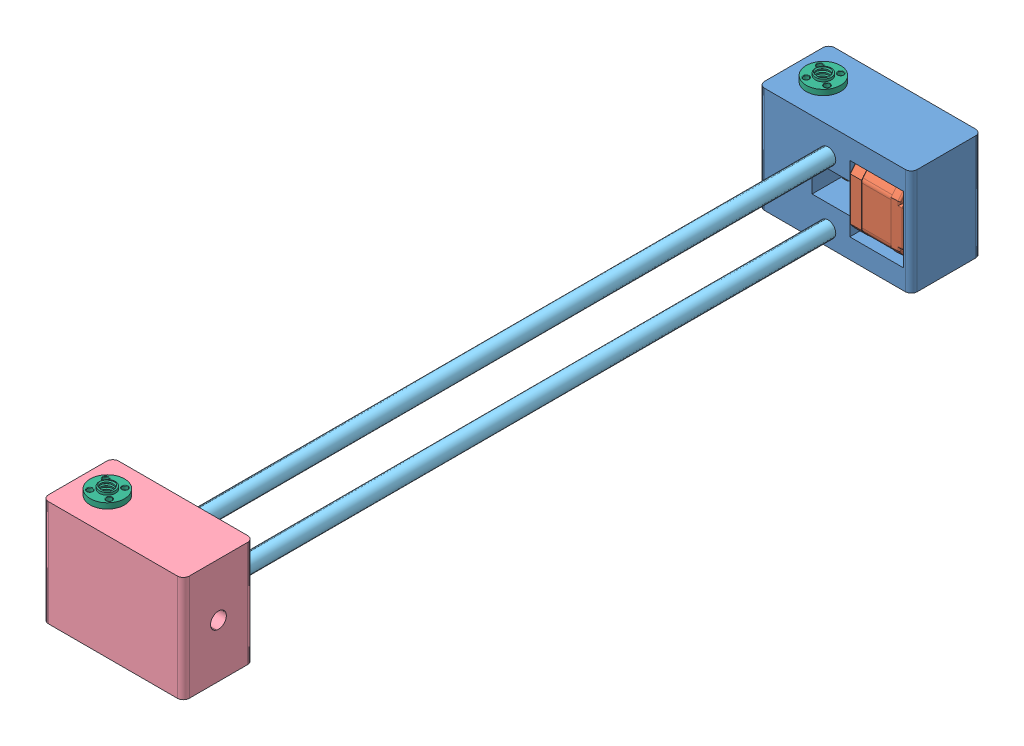
SolidWorks assembly Hot end shaft unit, configuration Default. Lengths in mm.
Overall size (97.79 73.34 503.43).
9 component instances, 6 part files, 27 mates.
Components (placement in the parent):
- Hot end motor housing-1: Hot end motor housing [Default] at (79.4555 45.3939 50.1961) size (97.79 67.82 44.96)
- Stepper Motor-1: Stepper Motor [6627T66] at (87.0755 66.6029 71.4051) x (0 0 1) z (-1 0 0) size (42.42 42.97 58.17)
- Timing Belt Sprocket-1: Timing Belt Sprocket [Défaut] at (82.5797 66.6029 71.4051) x (0 -0.226657 0.973975) z (-1 0 0) size (17.4 17.4 14.3)
- Hot end housing-1: Hot end housing [Default] at (28.6555 32.6939 551.0841) x (0 0 -1) z (1 0 0) size (44.96 67.82 90.17)
- Linear shaft 10mm-1: Linear shaft 10mm [6459K16] at (73.1055 83.3539 299.3701) size (10 10 426.21)
- Linear shaft 10mm-2: Linear shaft 10mm [6459K16] at (73.1055 42.8539 299.3701) size (10 10 426.21)
- Timing Belt Sprocket-2: Timing Belt Sprocket [Défaut] at (82.5035 66.7299 528.6051) x (0 0 1) z (-1 0 0) size (17.4 17.4 14.3)
- LeadScrew_Nut-1: LeadScrew_Nut [Default] at (47.7055 104.0119 70.1351) x (-0.837169 0 -0.546944) z (0 1 0) size (22 22 16.05)
- LeadScrew_Nut-2: LeadScrew_Nut [Default] at (47.7055 104.0119 528.6051) x (-0.773768 0 -0.633469) z (0 1 0) size (22 22 16.05)
Mates (geometry in assembly coordinates):
- Coincident1: coincident anti-aligned: plane of Hot end motor housing-1 through (79.4555 45.3939 50.1961) normal (0 0 1); plane of Stepper Motor-1 through (94.6447 52.7191 50.1961) normal (0 0 -1)
- Coincident2: coincident anti-aligned: plane of Hot end motor housing-1 through (121.3655 45.3939 92.6141) normal (-1 0 0); plane of Stepper Motor-1 through (121.3655 66.6029 71.4051) normal (1 0 0)
- Coincident3: coincident anti-aligned: plane of Hot end motor housing-1 through (87.0755 45.3939 92.6141) normal (0 1 0); plane of Stepper Motor-1 through (94.6447 45.3939 85.2889) normal (0 -1 0)
- Concentric2: concentric anti-aligned: cylinder of Stepper Motor-1 through (63.1995 66.6029 71.4051) axis (-1 0 0) radius 2.4956; cylinder of Timing Belt Sprocket-1 through (68.2795 66.6029 71.4051) axis (1 0 0) radius 3.175
- Distance1: distance = 5.08 mm aligned: plane of Stepper Motor-1 through (63.1995 69.0985 71.4051) normal (-1 0 0); plane of Timing Belt Sprocket-1 through (68.2795 66.6029 71.4051) normal (-1 0 0)
- Parallel1: parallel aligned: plane of Hot end motor housing-1 through (79.4555 45.3939 92.6141) normal (0 0 1); plane of Hot end housing-1 through (118.8255 32.6939 551.0841) normal (0 0 1)
- Coincident7: coincident aligned: plane of Hot end motor housing-1 through (28.6555 100.5119 92.6141) normal (0 1 0); plane of Hot end housing-1 through (118.8255 100.5119 551.0841) normal (0 1 0)
- Distance2: distance = 458.47 mm: cylinder of Hot end housing-1 through (47.7055 85.2719 528.6051) axis (0 1 0) radius 5.1; cylinder of Hot end motor housing-1 through (47.7055 85.2719 70.1351) axis (0 1 0) radius 5.1
- Concentric4: concentric anti-aligned: cylinder of Hot end motor housing-1 through (73.1055 83.3539 86.2641) axis (0 0 1) radius 5; cylinder of Linear shaft 10mm-1 through (73.1055 83.3539 512.4761) axis (0 0 -1) radius 5
- Coincident10: coincident anti-aligned: plane of Hot end housing-1 through (73.1055 83.3539 512.4761) normal (0 0 -1); plane of Linear shaft 10mm-1 through (73.1055 83.3539 512.4761) normal (0 0 1)
- Concentric5: concentric aligned: cylinder of Hot end housing-1 through (73.1055 42.8539 512.4761) axis (0 0 -1) radius 5; cylinder of Linear shaft 10mm-2 through (73.1055 42.8539 512.4761) axis (0 0 -1) radius 5
- Coincident11: coincident anti-aligned: plane of Hot end motor housing-1 through (73.1055 42.8539 86.2641) normal (0 0 1); plane of Linear shaft 10mm-2 through (73.1055 42.8539 86.2641) normal (0 0 -1)
- Concentric6: concentric aligned: cylinder of Hot end motor housing-1 through (47.7055 85.2719 70.1351) axis (0 1 0) radius 5.1; cylinder of Lead Screw Nut-1 through (47.7055 85.8275 70.1351) axis (0 1 0) radius 9.9949
- Coincident12: coincident anti-aligned: plane of Hot end motor housing-1 through (28.6555 100.5119 92.6141) normal (0 1 0); plane of Lead Screw Nut-1 through (47.7055 100.5119 70.1351) normal (0 -1 0)
- Concentric7: concentric aligned: cylinder of Hot end housing-1 through (47.7055 85.2719 528.6051) axis (0 1 0) radius 5.1; cylinder of Lead Screw Nut-2 through (47.7055 85.8275 528.6051) axis (0 1 0) radius 9.9949
- Coincident13: coincident anti-aligned: plane of Hot end housing-1 through (118.8255 100.5119 551.0841) normal (0 1 0); plane of Lead Screw Nut-2 through (47.7055 100.5119 528.6051) normal (0 -1 0)
- Concentric8: concentric aligned: cylinder of Hot end housing-1 through (68.0255 66.7299 528.6051) axis (1 0 0) radius 5.08; cylinder of Timing Belt Sprocket-2 through (68.2033 66.7299 528.6051) axis (1 0 0) radius 3.175
- Distance3: distance = 36.322 mm aligned: plane of Hot end housing-1 through (118.8255 32.6939 551.0841) normal (1 0 0); plane of Timing Belt Sprocket-2 through (82.5035 66.7299 528.6051) normal (1 0 0)
- Coincident14: coincident aligned: plane of Hot end motor housing-1 through (28.6555 32.6939 92.6141) normal (0 -1 0); plane of Hot end housing-1 through (118.8255 32.6939 551.0841) normal (0 -1 0)
- Concentric9: concentric aligned: cylinder of Hot end housing-1 through (73.1055 83.3539 512.4761) axis (0 0 -1) radius 5; cylinder of Linear shaft 10mm-1 through (73.1055 83.3539 512.4761) axis (0 0 -1) radius 5
- Concentric10: concentric anti-aligned: cylinder of Hot end motor housing-1 through (73.1055 42.8539 86.2641) axis (0 0 1) radius 5; cylinder of Linear shaft 10mm-2 through (73.1055 42.8539 512.4761) axis (0 0 -1) radius 5
- Concentric11: concentric aligned: cylinder of Hot end motor housing-1 through (47.7055 85.2719 70.1351) axis (0 1 0) radius 5.1; cylinder of LeadScrew_Nut-1 through (47.7055 90.5119 70.1351) axis (0 1 0) radius 5.1
- Coincident15: coincident anti-aligned: plane of Hot end motor housing-1 through (28.6555 100.5119 92.6141) normal (0 1 0); plane of LeadScrew_Nut-1 through (47.7055 100.5119 70.1351) normal (0 -1 0)
- Concentric13: concentric aligned: cylinder of Hot end housing-1 through (47.7055 85.2719 528.6051) axis (0 1 0) radius 5.1; cylinder of LeadScrew_Nut-2 through (47.7055 90.5119 528.6051) axis (0 1 0) radius 5.1
- Coincident16: coincident anti-aligned: plane of Hot end housing-1 through (118.8255 100.5119 551.0841) normal (0 1 0); plane of LeadScrew_Nut-2 through (47.7055 100.5119 528.6051) normal (0 -1 0)
- Lock1: lock: unknown of Hot end housing-1; unknown of LeadScrew_Nut-2
- Lock2: lock: unknown of Hot end motor housing-1; unknown of LeadScrew_Nut-1
